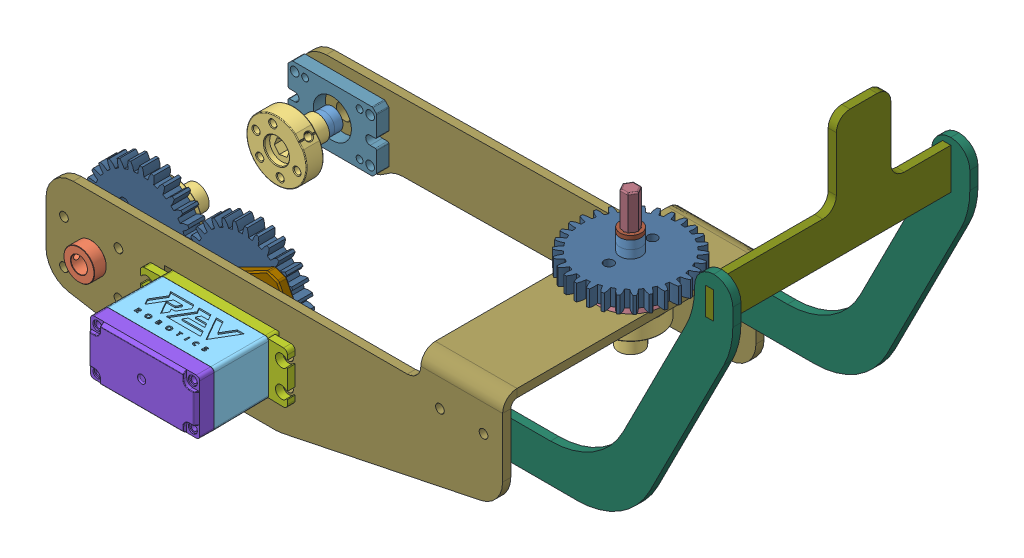
SolidWorks assembly Pitch Roll, configuration Valor predeterminado. Lengths in mm.
Overall size (261.18 162.18 129.85).
32 component instances, 17 part files, 61 mates.
Components (placement in the parent):
- Eixo 90mm-1: Eixo 90mm [Valor predeterminado] at (-348.9868 -139.7168 476.6342) x (-0.767956 -0.640503 0) z (0 0 -1) (suppressed, hidden)
- Espacador 3mm-1: Espacador 3mm [Default] at (-398.4358 -35.0705 427.1342) x (-0.797274 0.603617 0) z (0 0 -1) size (7.77 7.77 3)
- Fixador eixo REV-1: Fixador eixo REV [Default] at (-306.7476 -104.4878 442.1342) x (0.116527 0.993188 0) z (0 0 -1) size (11.25 11.25 4.5)
- Luva hex-1: Luva hex [Default] at (-306.7476 -104.4878 403.2842) x (-0.228261 -0.9736 0) z (0.9736 -0.228261 0) size (21.75 15 22)
- Espacador-2: Espacador [Valor predeterminado] at (-166.7476 -67.1878 384.1342) x (0 0 -1) z (1 0 0) size (23.2 6 23.2)
- Servo REV-2: Servo REV [Valor predeterminado] at (-293.3651 -106.4252 476.2501) x (0 -1 0) z (1 0 0) size (20.15 43.7 54)
  - E-1: E [Valor predeterminado] at (-1.9374 4.766 34.4654) size (20.15 20.1 40.15)
  - D-1: D [Valor predeterminado] at (-1.9374 34.866 24.4128) x (-1 0 0) z (0 0 -1) size (17.24 14.7 17.23)
  - C-1: C [Valor predeterminado] at (-1.9374 4.766 34.4654) size (19.8 13.29 54)
  - A-1: A [Valor predeterminado] at (-1.9374 4.766 34.4654) size (20.15 8.55 40.13)
- Adaptador servo REV-4: Adaptador servo REV [Default] at (-268.9524 -104.4878 427.7842) x (-0.892467 -0.451112 0) z (0 0 -1) size (40 13 7)
- Engranagem padrao-4: Engranagem padrao [Default] at (-268.9524 -104.4878 418.2842) x (0 0 1) z (-0.451112 0.892467 0) size (6 40.64 40.51)
- Espacador 3mm-2: Espacador 3mm [Default] at (-374.9894 -197.0542 433.1342) x (-0.593396 -0.80491 0) z (0 0 -1) size (7.77 7.77 3)
- Espacador 3mm-3: Espacador 3mm [Default] at (-203.226 -154.5755 430.1342) x (0.900171 -0.435537 0) z (0 0 -1) size (7.77 7.77 3)
- Espacador 3mm-5: Espacador 3mm [Default] at (-244.4077 -201.1275 353.6342) x (0.542076 -0.840329 0) z (0 0 1) size (7.77 7.77 3)
- Espacador 3mm-6: Espacador 3mm [Default] at (-203.1306 -54.5979 356.6342) x (0.901001 0.433817 0) z (0 0 1) size (7.77 7.77 3)
- Fixador eixo REV-2: Fixador eixo REV [Default] at (-306.7476 -104.4878 346.1342) x (0.950312 -0.311299 0) z (0 0 1) size (11.25 11.25 4.5)
- Luva hex-2: Luva hex [Default] at (-166.7476 -91.1878 384.1342) x (-0.866025 0 -0.5) z (-0.5 0 0.866025) size (21.75 15 22)
- Engranagem padrao-6: Engranagem padrao [Default] at (-166.7476 -67.1878 384.1342) x (0 1 0) z (1 0 0) size (6 40.64 40.51)
- Espacador 1.5mm-2: Espacador 1.5mm [Default] at (-428.759 -149.3628 434.6342) x (-0.938534 -0.345187 0) z (0 0 -1) size (7.77 7.77 1.5)
- Base dobrada-1: Base dobrada [Valor predeterminado] at (-166.7476 -73.1878 394.1342) x (-1 0 0) z (0 -1 0) size (167.6 96 52.3)
- Engranagem padrao-7: Engranagem padrao [Default] at (-306.7476 -104.4878 418.2842) x (0 0 1) z (0.68448 0.729032 0) size (6 40.64 40.51)
- Luva hex-3: Luva hex [Default] at (-306.7476 -104.4878 359.1342) x (0.767956 0.640503 0) z (-0.640503 0.767956 0) size (21.75 15 22)
- Eixo 30mm-1: Eixo 30mm [Valor predeterminado] at (-166.7476 -61.1878 384.1342) size (5.77 50 5)
- Espacador 1.5mm-3: Espacador 1.5mm [Default] at (-37.8798 -55.1878 366.9976) x (0.991274 0 -0.131817) z (0 1 0) size (7.77 7.77 1.5)
- Espacador 3mm-7: Espacador 3mm [Default] at (-51.7454 -58.1878 384.1342) x (1 0 0) z (0 1 0) size (7.77 7.77 3)
- Espacador 3mm-9: Espacador 3mm [Default] at (-51.7454 -61.1878 384.1342) x (1 0 0) z (0 1 0) size (7.77 7.77 3)
- Mancal REV1-1: Mancal REV1 [Valor predeterminado] at (-306.7476 -104.4878 434.6342) x (0 -1 0) z (0 0 1) size (22 32.5 4.5)
- Mancal REV1-2: Mancal REV1 [Valor predeterminado] at (-306.7476 -104.4878 353.6342) x (0 -1 0) z (0 0 -1) size (22 32.5 4.5)
- Braco batente-1: Braco batente [Valor predeterminado] at (-183.7476 -81.4878 352.1342) x (1 0 0) z (0 0 -1) size (109.5 97 3)
- Braco batente-3: Braco batente [Valor predeterminado] at (-183.7476 -81.4878 439.1342) x (1 0 0) z (0 0 -1) size (109.5 97 3)
- Batente-1: Batente [Valor predeterminado] at (-81.2476 -8.4878 394.1342) x (0 0 -1) z (-1 0 0) size (82 45 3)
Mates (geometry in assembly coordinates):
- Coincidente23: coincident anti-aligned: plane of Servo REV-2/D-1 through (-268.9524 -104.4878 427.7842) normal (0 0 -1); plane of Adaptador servo REV-4 through (-268.9524 -104.4878 427.7842) normal (0 0 1)
- Concêntrico22: concentric anti-aligned: circle of Servo REV-2/D-1; cylinder of Adaptador servo REV-4 through (-268.9524 -104.4878 427.7842) axis (0 0 -1) radius 1.6
- Coincidente24: coincident anti-aligned: plane of Adaptador servo REV-4 through (-268.9524 -104.4878 424.2842) normal (0 0 -1); plane of Engranagem padrao-4 through (-268.9524 -104.4878 424.2842) normal (0 0 1)
- Concêntrico23: concentric anti-aligned: cylinder of Adaptador servo REV-4 through (-268.9524 -104.4878 426.5342) axis (0 0 -1) radius 4.25; cylinder of Engranagem padrao-4 through (-268.9524 -104.4878 366.5785) axis (0 0 1) radius 3
- Concêntrico24: concentric anti-aligned: cylinder of Adaptador servo REV-4 through (-261.8126 -100.8789 427.7842) axis (0 0 -1) radius 1.25; cylinder of Engranagem padrao-4 through (-261.8126 -100.8789 366.5785) axis (0 0 1) radius 1.75
- Coincidente34: coincident aligned: circle of Espacador 3mm-5; circle of Espacador 3mm-6
- Coincidente37: coincident aligned: circle of Espacador 3mm-2; circle of Espacador 3mm-3
- Coincidente39: coincident aligned: circle of Espacador 3mm-1; circle of Espacador 3mm-3
- Concêntrico52: concentric aligned: cylinder of Luva hex-2 through (-166.7476 -78.2378 384.1342) axis (0 1 0) radius 4.55; cylinder of Engranagem padrao-6 through (-166.7476 -118.8934 384.1342) axis (0 1 0) radius 3
- Concêntrico53: concentric aligned: circle of Luva hex-2; cylinder of Engranagem padrao-6 through (-166.7476 -118.8934 392.1342) axis (0 1 0) radius 1.75
- Concêntrico54: concentric anti-aligned: cylinder of Espacador-2 through (-166.7476 -67.1878 384.1342) axis (0 -1 0) radius 3; cylinder of Engranagem padrao-6 through (-166.7476 -118.8934 384.1342) axis (0 1 0) radius 3
- Concêntrico55: concentric anti-aligned: cylinder of Espacador-2 through (-166.7476 -67.1878 392.1342) axis (0 -1 0) radius 1.6; cylinder of Engranagem padrao-6 through (-166.7476 -118.8934 392.1342) axis (0 1 0) radius 1.75
- Coincidente55: coincident aligned: circle of Espacador 3mm-2; circle of Espacador 1.5mm-2
- Coincidente58: coincident anti-aligned: plane of Fixador eixo REV-1 through (-306.7476 -104.4878 442.1342) normal (0 0 -1); plane of Base dobrada-1 through (-190.7476 -78.4878 442.1342) normal (0 0 1)
- Concêntrico65: concentric aligned: cylinder of Servo REV-2/C-1 through (-234.1498 -109.4878 442.1342) axis (0 0 -1) radius 2.25; cylinder of Base dobrada-1 through (-234.1498 -109.4878 442.1342) axis (0 0 -1) radius 1.6
- Coincidente59: coincident: line of Servo REV-2/C-1 through (-238.9992 -95.8621 442.1342) axis (0 -1 0); plane of Base dobrada-1 through (-190.7476 -78.4878 442.1342) normal (0 0 1)
- Concêntrico66: concentric aligned: cylinder of Servo REV-2/C-1 through (-283.6498 -109.4878 442.1342) axis (0 0 -1) radius 2.25; cylinder of Base dobrada-1 through (-283.6498 -109.4878 442.1342) axis (0 0 -1) radius 1.6
- Coincidente60: coincident anti-aligned: plane of Fixador eixo hex-2 through (-306.7476 -104.4878 346.1342) normal (0 0 1); plane of Base dobrada-1 through (-190.7476 -83.2522 346.1342) normal (0 0 -1)
- Concêntrico67: concentric aligned: cylinder of Luva hex-2 through (-166.7476 -76.1878 384.1342) axis (0 -1 0) radius 4.45; cylinder of Base dobrada-1 through (-166.7476 -76.1878 384.1342) axis (0 -1 0) radius 4.5
- Concêntrico68: concentric aligned: cylinder of Luva hex-2 through (-166.7476 -82.4378 392.1342) axis (0 -1 0) radius 1.25; cylinder of Base dobrada-1 through (-166.7476 -76.1878 392.1342) axis (0 -1 0) radius 1.6
- Coincidente61: coincident anti-aligned: plane of Luva hex-2 through (-166.7476 -76.1878 384.1342) normal (0 1 0); plane of Base dobrada-1 through (-166.7476 -76.1878 394.1342) normal (0 -1 0)
- Coincidente62: coincident anti-aligned: plane of Espacador-2 through (-166.7476 -73.1878 384.1342) normal (0 -1 0); plane of Base dobrada-1 through (-166.7476 -73.1878 394.1342) normal (0 1 0)
- Coincidente63: coincident anti-aligned: plane of Espacador-2 through (-166.7476 -67.1878 384.1342) normal (0 1 0); plane of Engranagem padrao-6 through (-166.7476 -67.1878 384.1342) normal (0 -1 0)
- Coincidente70: coincident anti-aligned: plane of Luva hex-1 through (-306.7476 -104.4878 418.2842) normal (0 0 1); plane of Engranagem padrao-7 through (-306.7476 -104.4878 418.2842) normal (0 0 -1)
- Concêntrico70: concentric aligned: cylinder of Luva hex-1 through (-306.7476 -104.4878 416.2342) axis (0 0 1) radius 4.55; cylinder of Engranagem padrao-7 through (-306.7476 -104.4878 366.5785) axis (0 0 1) radius 3
- Concêntrico71: concentric anti-aligned: cylinder of Luva hex-1 through (-312.5798 -99.0119 412.0342) axis (0 0 -1) radius 1.25; cylinder of Engranagem padrao-7 through (-312.5798 -99.0119 366.5785) axis (0 0 1) radius 1.75
- Coincidente77: coincident aligned: plane of Engranagem padrao-4 through (-268.9524 -104.4878 424.2842) normal (0 0 1); plane of Engranagem padrao-7 through (-306.7476 -104.4878 424.2842) normal (0 0 1)
- Distância3: distance = 25 mm aligned: plane of Base dobrada-1 through (-190.7476 -83.2522 349.1342) normal (0 0 1); plane of Luva hex-3 through (-306.7476 -104.4878 374.1342) normal (0 0 1)
- Coincidente78: coincident aligned: line of Eixo 90mm-1 through (-304.8986 -106.7047 446.1342) axis (0 0 -1); line of Luva hex-3 through (-304.8986 -106.7047 372.0842) axis (0 0 -1)
- Coincidente79: coincident anti-aligned: plane of Eixo 90mm-1 through (-304.8986 -106.7047 446.6342) normal (0.170714 -0.985321 0); plane of Luva hex-3 through (-304.8986 -106.7047 374.1342) normal (-0.170714 0.985321 0)
- Coincidente82: coincident aligned: plane of Eixo 90mm-1 through (-348.9868 -139.7168 341.6342) normal (0 0 -1); plane of Fixador eixo REV-2 through (-306.7476 -104.4878 341.6342) normal (0 0 -1)
- Coincidente83: coincident aligned: plane of Luva hex-2 through (-166.7476 -91.1878 384.1342) normal (0 -1 0); plane of Eixo 30mm-1 through (-166.7476 -91.1878 384.1342) normal (0 -1 0)
- Coincidente84: coincident aligned: line of Luva hex-2 through (-165.3042 -78.2378 381.6342) axis (0 -1 0); line of Eixo 30mm-1 through (-165.3042 -41.6878 381.6342) axis (0 -1 0)
- Coincidente85: coincident anti-aligned: plane of Luva hex-2 through (-163.8608 -76.1878 384.1342) normal (-0.866025 0 -0.5); plane of Eixo 30mm-1 through (-163.8608 -41.1878 384.1342) normal (0.866025 0 0.5)
- Coincidente86: coincident aligned: circle of Espacador 1.5mm-3; circle of Espacador 3mm-7
- Coincidente87: coincident aligned: circle of Espacador 3mm-7; circle of Espacador 3mm-9
- Concêntrico76: concentric anti-aligned: circle of Engranagem padrao-6; cylinder of Espacador 3mm-9 through (-166.7476 -58.1878 384.1342) axis (0 -1 0) radius 3.8868
- Coincidente88: coincident anti-aligned: plane of Engranagem padrao-6 through (-166.7476 -61.1878 384.1342) normal (0 1 0); plane of Espacador 3mm-9 through (-137.2476 -61.1878 384.1342) normal (0 -1 0)
- Concêntrico77: concentric anti-aligned: circle of Base dobrada-1; cylinder of Mancal REV1-1 through (-296.7476 -112.4878 439.1342) axis (0 0 -1) radius 1.25
- Concêntrico79: concentric aligned: cylinder of Fixador eixo REV-1 through (-306.7476 -104.4878 446.6342) axis (0 0 -1) radius 5.625; cylinder of Mancal REV1-1 through (-306.7476 -104.4878 439.1342) axis (0 0 -1) radius 7
- Concêntrico80: concentric aligned: cylinder of Base dobrada-1 through (-316.7476 -96.4878 442.1342) axis (0 0 -1) radius 1.6; cylinder of Mancal REV1-1 through (-316.7476 -96.4878 439.1342) axis (0 0 -1) radius 1.25
- Coincidente89: coincident anti-aligned: plane of Base dobrada-1 through (-190.7476 -78.4878 439.1342) normal (0 0 -1); plane of Mancal REV1-1 through (-290.9976 -106.5878 439.1342) normal (0 0 1)
- Coincidente91: coincident anti-aligned: plane of Base dobrada-1 through (-190.7476 -83.2522 349.1342) normal (0 0 1); plane of Mancal REV1-2 through (-322.4976 -106.5878 349.1342) normal (0 0 -1)
- Concêntrico81: concentric aligned: cylinder of Base dobrada-1 through (-316.7476 -96.4878 346.1342) axis (0 0 1) radius 1.6; cylinder of Mancal REV1-2 through (-316.7476 -96.4878 349.1342) axis (0 0 1) radius 1.25
- Concêntrico82: concentric aligned: cylinder of Base dobrada-1 through (-316.7476 -112.4878 346.1342) axis (0 0 1) radius 1.6; cylinder of Mancal REV1-2 through (-316.7476 -112.4878 349.1342) axis (0 0 1) radius 1.25
- Concêntrico83: concentric anti-aligned: cylinder of Luva hex-3 through (-306.7476 -104.4878 374.1342) axis (0 0 -1) radius 4.45; cylinder of Mancal REV1-2 through (-306.7476 -104.4878 349.1342) axis (0 0 1) radius 7
- Concêntrico84: concentric aligned: cylinder of Luva hex-1 through (-306.7476 -104.4878 418.2842) axis (0 0 -1) radius 4.45; cylinder of Luva hex-3 through (-306.7476 -104.4878 374.1342) axis (0 0 -1) radius 4.45
- Concêntrico85: concentric anti-aligned: cylinder of Fixador eixo REV-2 through (-306.7476 -104.4878 341.6342) axis (0 0 1) radius 5.625; cylinder of Luva hex-3 through (-306.7476 -104.4878 374.1342) axis (0 0 -1) radius 4.45
- Concêntrico86: concentric aligned: cylinder of Espacador 3mm-5 through (-306.7476 -104.4878 356.6342) axis (0 0 -1) radius 3.8868; cylinder of Luva hex-3 through (-306.7476 -104.4878 374.1342) axis (0 0 -1) radius 4.45
- Coincidente92: coincident anti-aligned: plane of Espacador 3mm-5 through (-290.7563 -129.2775 353.6342) normal (0 0 -1); plane of Mancal REV1-2 through (-322.4976 -106.5878 353.6342) normal (0 0 1)
- Concêntrico87: concentric anti-aligned: cylinder of Espacador 3mm-1 through (-306.7476 -104.4878 424.1342) axis (0 0 1) radius 3.8868; cylinder of Luva hex-1 through (-306.7476 -104.4878 418.2842) axis (0 0 -1) radius 4.45
- Coincidente93: coincident anti-aligned: plane of Espacador 1.5mm-2 through (-348.5123 -119.8486 434.6342) normal (0 0 1); plane of Mancal REV1-1 through (-290.9976 -106.5878 434.6342) normal (0 0 -1)
- Coincidente94: coincident aligned: circle of Base dobrada-1; cylinder of Braco batente-1 through (-178.7476 -88.4878 349.1342) axis (0 0 1) radius 1.6
- Coincidente95: coincident anti-aligned: cylinder of Base dobrada-1 through (-162.7476 -88.4878 346.1342) axis (0 0 1) radius 1.6; circle of Braco batente-1
- Coincidente96: coincident anti-aligned: plane of Base dobrada-1 through (-190.7476 -83.2522 349.1342) normal (0 0 1); plane of Braco batente-1 through (-183.7476 -81.4878 349.1342) normal (0 0 -1)
- Coincidente97: coincident aligned: circle of Base dobrada-1; cylinder of Braco batente-3 through (-178.7476 -88.4878 436.1342) axis (0 0 1) radius 1.6
- Concêntrico88: concentric anti-aligned: circle of Base dobrada-1; circle of Braco batente-3
- Coincidente99: coincident anti-aligned: plane of Base dobrada-1 through (-190.7476 -78.4878 439.1342) normal (0 0 -1); plane of Braco batente-3 through (-183.7476 -81.4878 439.1342) normal (0 0 1)
- Coincidente100: coincident anti-aligned: plane of Braco batente-1 through (-84.2476 -3.4878 349.1342) normal (1 0 0); plane of Batente-1 through (-84.2476 -8.4878 394.1342) normal (-1 0 0)
- Coincidente101: coincident aligned: plane of Braco batente-1 through (-183.7476 -81.4878 349.1342) normal (0 0 -1); plane of Batente-1 through (-84.2476 -8.4878 349.1342) normal (0 0 -1)
- Coincidente102: coincident anti-aligned: plane of Braco batente-1 through (-84.2476 -13.4878 349.1342) normal (0 1 0); plane of Batente-1 through (-84.2476 -13.4878 394.1342) normal (0 -1 0)
